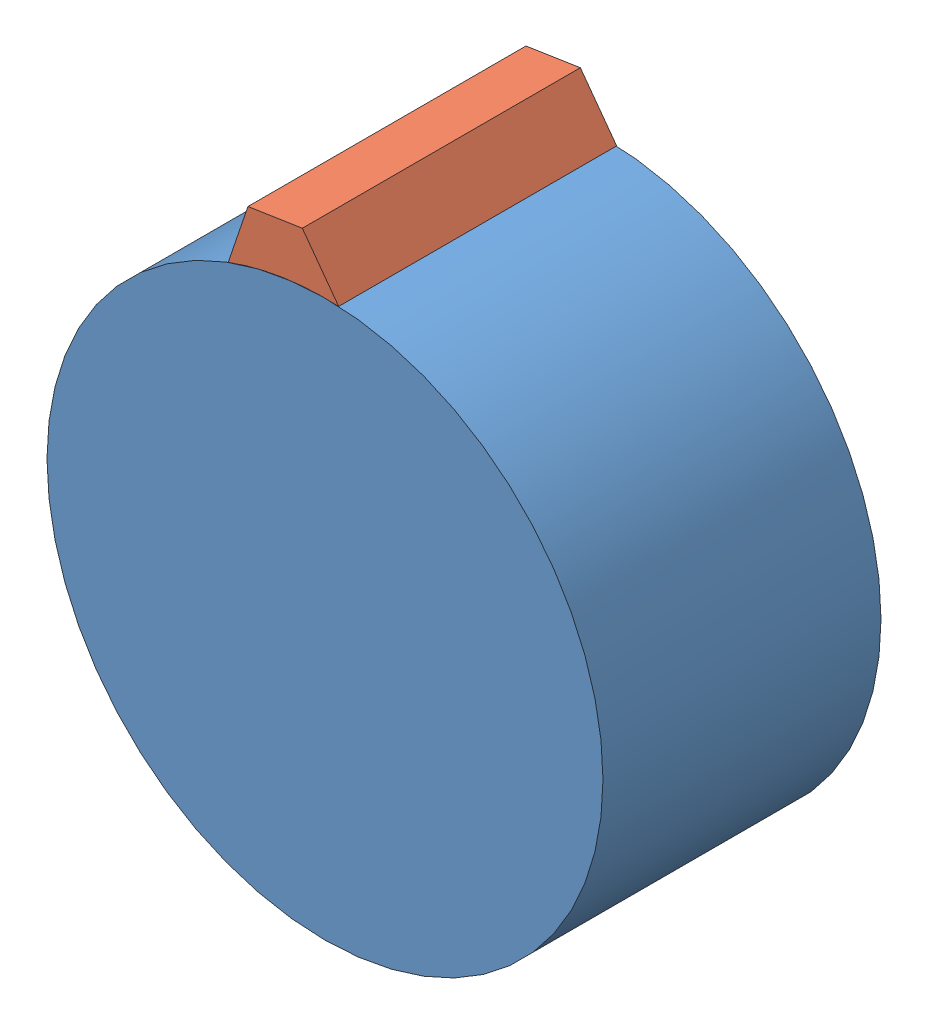
SolidWorks assembly Assem1, configuration Default. Lengths in mm.
Overall size (20 21.93 10).
2 component instances, 2 part files, 2 mates.
Components (placement in the parent):
- Part2-1: Part2 [Default] at (6.1687 11.5902 10.2526) size (20 20 10)
- Part3-1: Part3 [Default] at (6.1687 11.5902 10.2526) x (0.98829 0.152589 0) z (0 0 1) size (4.02 1.96 10)
Mates (geometry in assembly coordinates):
- Concentric1: concentric: cylinder of Part2-1 through (6.1687 11.5902 20.2526) axis (0 0 -1) radius 10; cylinder of Part3-1 through (6.1687 11.5902 20.2526) axis (0 0 -1) radius 10
- Coincident1: coincident: plane of Part2-1 through (6.1687 11.5902 20.2526) normal (0 0 1); plane of Part3-1 through (6.1687 11.5902 20.2526) normal (0 0 1)
